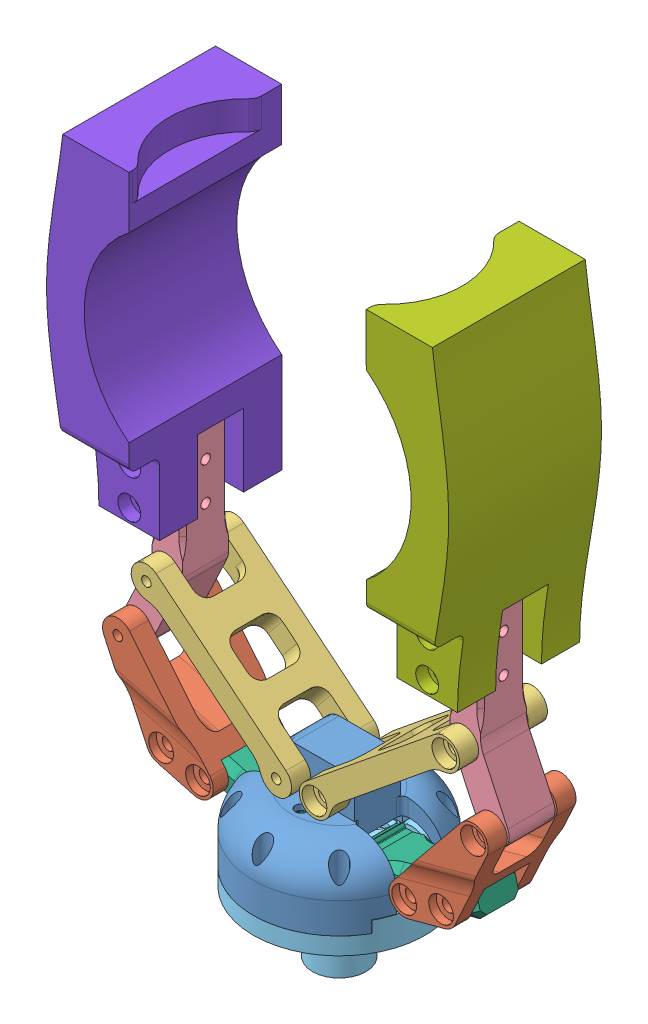
SolidWorks assembly gripper_urdf, configuration Default. Lengths in mm.
Overall size (113.33 174.21 46.5).
13 component instances, 8 part files, 6 mates.
Components (placement in the parent):
- HEBI Robotics-A-2143-02-1: HEBI Robotics-A-2143-02 [Default] at (-33.7642 -33.0468 7.6368) size (112.08 105.21 45)
  - HEBI Robotics-A-2143-02_PM-2357-02-1: HEBI Robotics-A-2143-02_PM-2357-02 [Default] at (0 30.9247 0) x (0 0 -1) z (1 0 0) size (45 28 44.67)
  - HEBI Robotics-A-2143-02_PM-2358-02-1: HEBI Robotics-A-2143-02_PM-2358-02 [Default] at (-31.436 29.5333 0) x (0 0 -1) z (0.966127 -0.258068 0) size (23 26 33)
  - HEBI Robotics-A-2143-02_PM-2358-02-2: HEBI Robotics-A-2143-02_PM-2358-02 [Default] at (31.4354 29.5354 0) x (0 0 1) z (-0.966125 -0.258076 0) size (23 26 33)
  - HEBI Robotics-A-2143-02_PM-2359-02-1: HEBI Robotics-A-2143-02_PM-2359-02 [Default] at (21.9996 52.7813 0) x (0 0 1) z (0.775123 0.631811 0) size (23 8 51.86)
  - HEBI Robotics-A-2143-02_PM-2359-02-2: HEBI Robotics-A-2143-02_PM-2359-02 [Default] at (-22.0004 52.7803 0) x (0 0 -1) z (-0.775159 0.631767 0) size (23 8 51.86)
  - HEBI Robotics-A-2143-02_PM-2360-02-1: HEBI Robotics-A-2143-02_PM-2360-02 [Default] at (-39.0008 66.6359 0) x (-1 -0.000025 0) z (0 0 -1) size (15.5 54 12.08)
  - HEBI Robotics-A-2143-02_PM-2360-02-2: HEBI Robotics-A-2143-02_PM-2360-02 [Default] at (38.9992 66.6378 0) x (1 0.000025 0) z (0 0 1) size (15.5 54 12.08)
  - HEBI Robotics-A-2055-01_PM-2218-01-1: HEBI Robotics-A-2055-01_PM-2218-01 [Default] at (0 11.4247 0) size (45 32.5 45)
  - HEBI Robotics-A-2055-01_PM-2221-01-1: HEBI Robotics-A-2055-01_PM-2221-01 [Default] at (12.5 22.9247 0) x (0.966125 0.258076 0) z (0 0 1) size (35.49 9.86 12)
  - HEBI Robotics-A-2055-01_PM-2221-01-2: HEBI Robotics-A-2055-01_PM-2221-01 [Default] at (-12.5 22.9247 0) x (-0.966162 0.257934 0) z (0 0 -1) size (35.49 9.86 12)
- gripper finger mirror-1: gripper finger mirror [Default] at (-20.9541 99.0903 -8.3632) x (1 0.000025 0) z (0.000025 -1 0) size (25.6 40 87.5)
- gripper finger-1: gripper finger [Default] at (-46.5791 99.0897 -8.3632) x (1 0.000025 0) z (0.000025 -1 0) size (25.6 40 87.5)
Mates (geometry in assembly coordinates):
- Concentric1: concentric: circle of HEBI Robotics-A-2143-02-1/HEBI Robotics-A-2143-02_PM-2360-02-1; circle of gripper finger-1
- Concentric2: concentric: circle of HEBI Robotics-A-2143-02-1/HEBI Robotics-A-2143-02_PM-2360-02-1; circle of gripper finger-1
- Coincident1: coincident anti-aligned: plane of HEBI Robotics-A-2143-02-1/HEBI Robotics-A-2143-02_PM-2360-02-1 through (-80.2646 17.5889 1.6368) normal (0 0 -1); plane of gripper finger-1 through (-46.5783 68.1397 1.6368) normal (0 0 1)
- Concentric3: concentric: circle of HEBI Robotics-A-2143-02-1/HEBI Robotics-A-2143-02_PM-2360-02-2; circle of gripper finger mirror-1
- Concentric4: concentric: circle of HEBI Robotics-A-2143-02-1/HEBI Robotics-A-2143-02_PM-2360-02-2; circle of gripper finger mirror-1
- Coincident2: coincident anti-aligned: plane of HEBI Robotics-A-2143-02-1/HEBI Robotics-A-2143-02_PM-2360-02-2 through (12.7354 17.5912 1.6368) normal (0 0 -1); plane of gripper finger mirror-1 through (-20.9533 68.1403 1.6368) normal (0 0 1)
